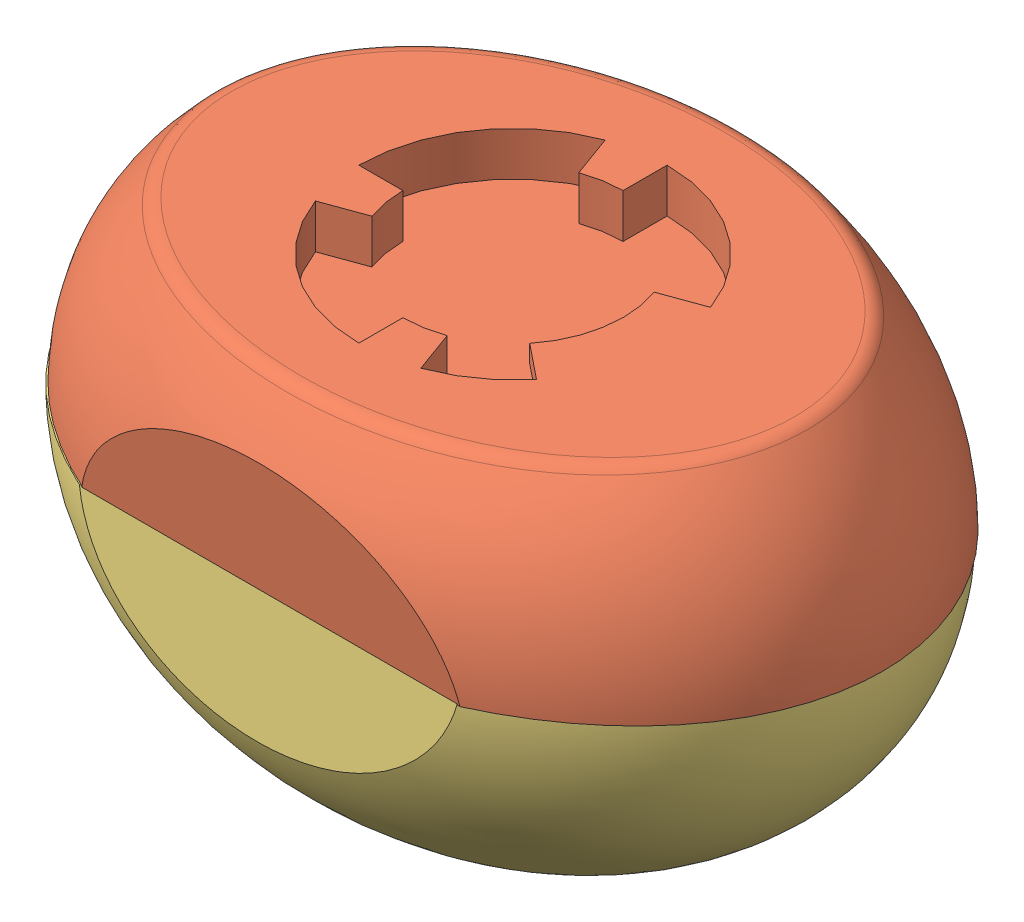
SolidWorks assembly EggAssembly, configuration Default. Lengths in mm.
Overall size (123.75 63.75 89.02).
3 component instances, 3 part files, 6 mates.
Components (placement in the parent):
- BoardIMU-1: BoardIMU [Default] at origin size (54 25 29)
- EggBottom-2: EggBottom [Default] at (-25.75 11.75 14.5) x (-1 0 0) z (0 -1 0) size (84 64 59.3)
- EggTop-2: EggTop [Default] at (-26 12 14.5) x (1 0 0) z (0 1 0) size (123.75 89.02 38.75)
Mates (geometry in assembly coordinates):
- Coincident1: coincident anti-aligned: plane of BoardIMU-1 through (-50 0 29) normal (0 -1 0); plane of EggTop-2 through (-26 0 14.5) normal (0 1 0)
- Distance3: distance = 2 mm anti-aligned: plane of BoardIMU-1 through (0 0 29) normal (1 0 0); plane of EggTop-2 through (2 0 -2) normal (-1 0 0)
- Distance4: distance = 2 mm anti-aligned: plane of BoardIMU-1 through (0 0 0) normal (0 0 -1); plane of EggTop-2 through (-52 0 -2) normal (0 0 1)
- Coincident9: coincident anti-aligned: plane of EggBottom-2 through (-25.75 18.75 14.5) normal (0 -1 0); plane of EggTop-2 through (-26 18.75 14.5) normal (0 1 0)
- Distance5: distance = 0.5 mm anti-aligned: plane of EggBottom-2 through (-2.75 18.75 -7) normal (0 0 1); plane of EggTop-2 through (-47.5 18.75 -6.5) normal (0 0 -1)
- Distance6: distance = 1.25 mm anti-aligned: plane of EggTop-2 through (-47.5 18.75 -6.5) normal (-1 0 0); plane of EggBottom-2 through (-48.75 18.75 -7) normal (1 0 0)
